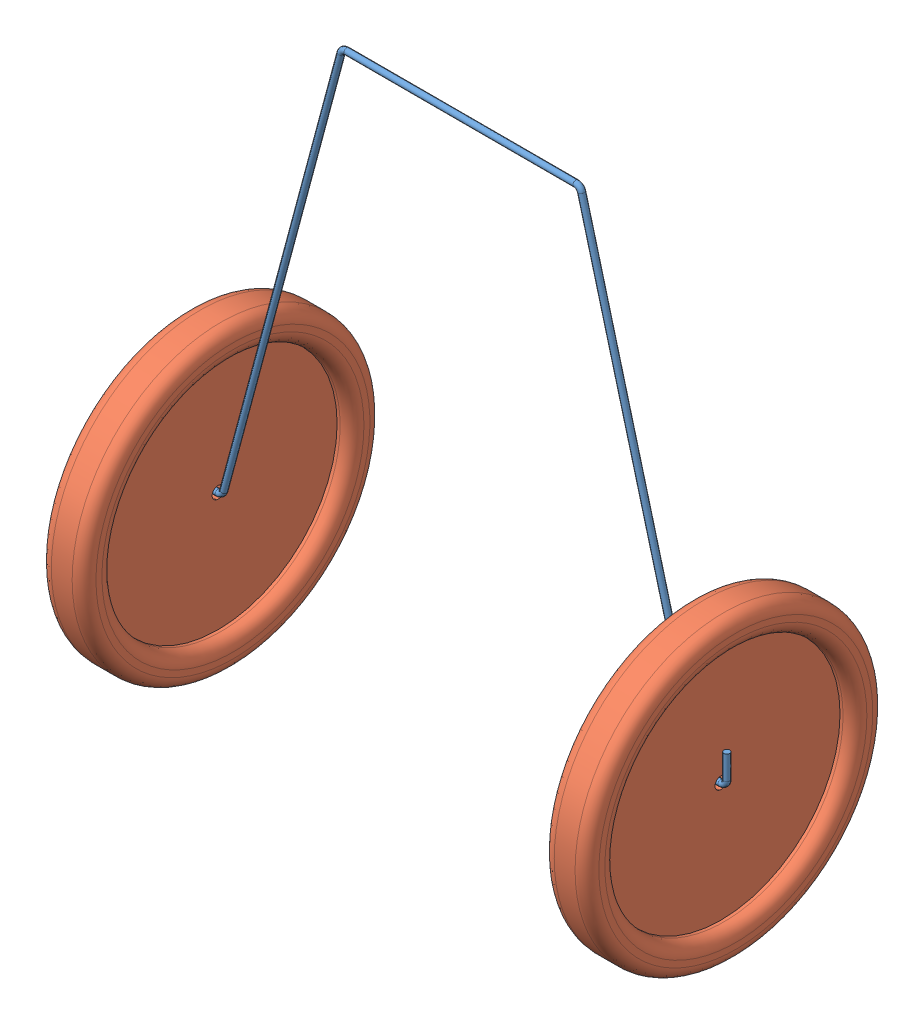
SolidWorks assembly Assem1, configuration Default. Lengths in mm.
Overall size (46.72 51.05 25.4).
3 component instances, 2 part files, 4 mates.
Components (placement in the parent):
- wheel wire-1: wheel wire [Default] at origin size (45.82 38.61 0.51)
- wheel-3: wheel [Default] at (-21.3937 -38.1 0) size (3.81 25.4 25.4)
- wheel-4: wheel [Default] at (21.5119 -38.1 0) size (3.81 25.4 25.4)
Mates (geometry in assembly coordinates):
- Concentric4: concentric: cylinder of wheel wire-1 through (20.7587 -38.1 0) axis (1 0 0) radius 0.254; cylinder of wheel-4 through (19.6069 -38.1 0) axis (1 0 0) radius 0.508
- Coincident4: coincident anti-aligned: circle of wheel wire-1; plane of wheel-4 through (22.1469 -27.94 0) normal (1 0 0)
- Concentric5: concentric: cylinder of wheel wire-1 through (-22.1469 -38.1 0) axis (1 0 0) radius 0.254; cylinder of wheel-3 through (-23.2987 -38.1 0) axis (1 0 0) radius 0.508
- Coincident5: coincident anti-aligned: circle of wheel wire-1; plane of wheel-3 through (-20.7587 -27.94 0) normal (1 0 0)
